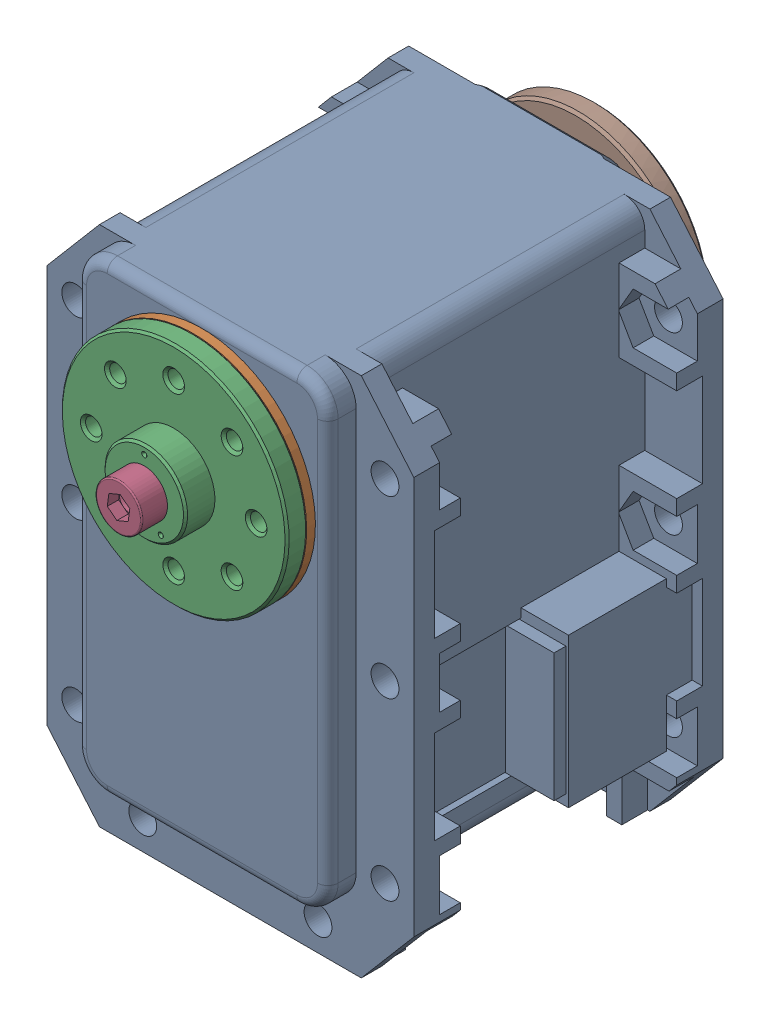
SolidWorks assembly MX-28(U)-7, configuration Default. Lengths in mm.
Overall size (35.6 54.13 48.5).
8 component instances, 7 part files, 0 mates.
Components (placement in the parent):
- dynamixel_x28series(U)-1: dynamixel_x28series(U) [Default] at origin size (35.6 50.71 41.85)
- trust_washer(U)-1: trust_washer(U) [Default] at (0 0 18.6) x (-0.666375 -0.745617 0) z (0.745617 -0.666375 0) size (22 0.85 22)
- HN07-N101(U)-1: HN07-N101(U) [Default] at (0 0 18.5) x (1 0 0) z (0 -1 0) size (22 5.85 22)
- WB_M2.5x8-1: WB_M2.5x8 [Default] at (0 0 25.85) x (0 0 -1) z (-0.991137 0.132843 0) size (10.5 4.5 4.5)
- WB_M2.5x8-2: WB_M2.5x8 [Default] at (0 0 -22.65) x (0 0 1) z (-0.936501 0.350665 0) size (10.5 4.5 4.5)
- RX28-CAP-1: RX28-CAP [Default] at (0 0 -20.35) x (-0.995735 -0.092256 0) z (0 0 -1) size (7.2 7.2 1.8)
- MF106ZZ-1: MF106ZZ [Default] at (0 0 -20.35) x (0.888333 -0.4592 0) z (-0.4592 -0.888333 0) size (11.2 3 11.2)
- HN07-i101-1: HN07-i101 [Default] at (0 0 -20.5) x (1 0 0) z (0 1 0) size (22 3.05 22)
